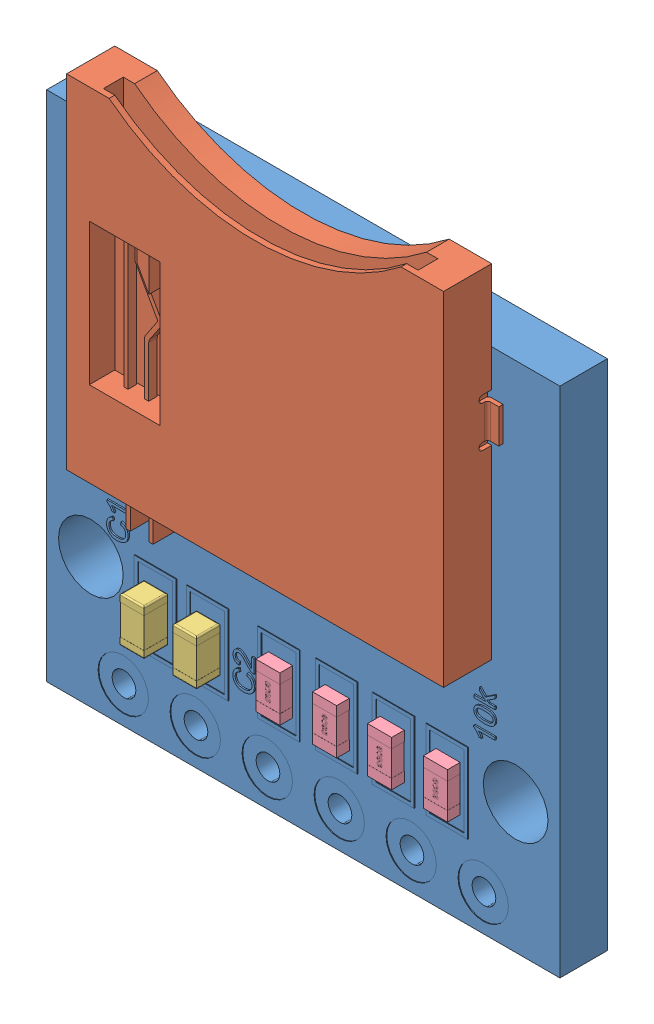
SolidWorks assembly MicroSD Card Module - 1, configuration Default. Lengths in mm.
Overall size (18.11 20.62 3.45).
9 component instances, 4 part files, 0 mates.
Components (placement in the parent):
- MicroSD Card Module - 1.stp-1: MicroSD Card Module - 1.stp [Default] at origin size (18.11 20.62 3.45)
  - Micro SD Module - 1.stp-1: Micro SD Module - 1.stp [Default] at origin size (18.11 18.08 1.84)
  - MicroSD.stp-1: MicroSD.stp [Default] at (0 5.5324 1.6764) x (-1 0 0) z (0 1 0) size (14.1 2.25 13.6)
  - 0603 Capacitor.stp-1: 0603 Capacitor.stp [Default] at (-4.7839 -5.8092 1.6739) x (0 1 0) z (0 0 1) size (1.6 0.84 0.84)
  - 0603 Resistor.stp-1: 0603 Resistor.stp [Default] at (-1.2256 -4.214 1.6739) x (0 -1 0) z (0 0 1) size (1.6 0.85 0.56)
  - 0603 Capacitor.stp-2: 0603 Capacitor.stp [Default] at (-2.9282 -5.8092 1.6739) x (0 1 0) z (0 0 1) size (1.6 0.84 0.84)
  - 0603 Resistor.stp-2: 0603 Resistor.stp [Default] at (0.7739 -4.214 1.6739) x (0 -1 0) z (0 0 1) size (1.6 0.85 0.56)
  - 0603 Resistor.stp-3: 0603 Resistor.stp [Default] at (2.7155 -4.214 1.6739) x (0 -1 0) z (0 0 1) size (1.6 0.85 0.56)
  - 0603 Resistor.stp-4: 0603 Resistor.stp [Default] at (4.6861 -4.214 1.6739) x (0 -1 0) z (0 0 1) size (1.6 0.85 0.56)
